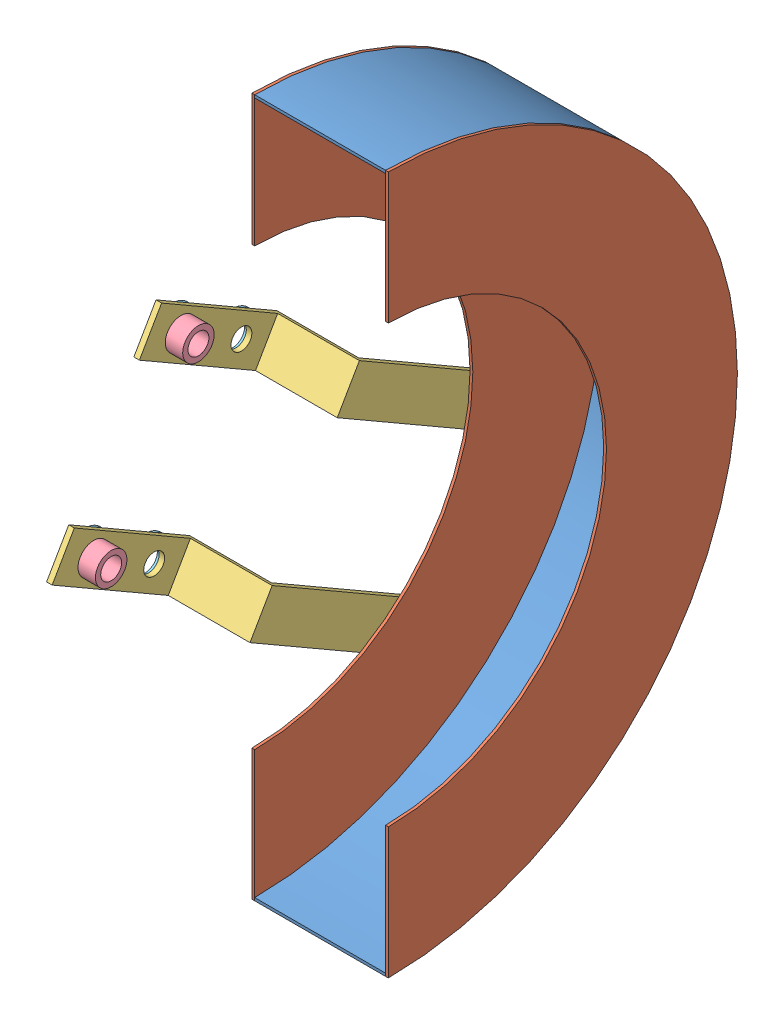
SolidWorks assembly 53model, configuration Default. Lengths in mm.
Overall size (130.17 400 267.8).
12 component instances, 5 part files, 17 mates.
Components (placement in the parent):
- 52model-1: 52model [Default] at (-9.646 -13.9168 14.5449) size (78.17 400 200)
  - GuardFlat-1: GuardFlat [Default] at (-13.9553 22.8327 72.0636) size (75 400 200)
  - GuardSide-1: GuardSide [Default] at (-15.5428 22.8327 72.0636) size (1.59 400 200)
  - GuardSide-2: GuardSide [Default] at (61.0447 22.8327 72.0636) size (1.59 400 200)
- GuardSupport-1: GuardSupport [Default] at (-75.1888 61.8019 104.2453) x (1 0 0) z (0 0.5 0.866025) size (50 25.4 236.83)
- GuardSupport-2: GuardSupport [Default] at (-75.1888 -24.8007 154.2453) x (1 0 0) z (0 0.5 0.866025) size (50 25.4 236.83)
- MediumNut-3: MediumNut [Default] at (-62.0138 -23.5423 130.4248) x (0 1 0) z (0 0 1) size (18 10 18)
- MediumNut-4: MediumNut [Default] at (-62.0138 63.0602 80.4248) x (0 1 0) z (0 0 1) size (18 10 18)
- 87model-1: 87model [Default] at (-77.1888 43.0602 45.7838) x (0 -1 0) z (0 0 1) size (25 2 25)
- 87model-2: 87model [Default] at (-77.1888 -23.5423 130.4248) x (0 -1 0) z (0 0 1) size (25 2 25)
- 87model-3: 87model [Default] at (-77.1888 63.0602 80.4248) x (0 -1 0) z (0 0 1) size (25 2 25)
- 87model-4: 87model [Default] at (-77.1888 -43.5423 95.7838) x (0 -1 0) z (0 0 1) size (25 2 25)
Mates (geometry in assembly coordinates):
- Coincident1: coincident anti-aligned: plane of 52model-1/GuardSide-1 through (-25.1888 8.9159 -353.5329) normal (-1 0 0); plane of GuardSupport-2 through (-25.1888 -121.2161 -63.5512) normal (1 0 0)
- Coincident2: coincident aligned: circle of 52model-1/GuardSide-1; plane of GuardSupport-1 through (-25.1888 -34.6136 -113.5512) normal (1 0 0)
- Distance1: distance = 100 mm aligned: plane of GuardSupport-1 through (-75.1888 61.8019 104.2453) normal (0 -0.866025 0.5); plane of GuardSupport-2 through (-75.1888 -24.8007 154.2453) normal (0 -0.866025 0.5)
- Coincident4: coincident: plane of GuardSupport-1 through (-72.0138 83.7989 91.5453) normal (0 0.5 0.866025); line of GuardSupport-2 through (-72.0138 -2.8036 141.5453) axis (0 -0.866025 0.5)
- Angle1: planar angle = 2.094395 rad aligned: plane of GuardSupport-1 through (-75.1888 83.7989 91.5453) normal (0 0.866025 -0.5); plane of 52model-1/GuardSide-1 through (-23.6013 8.9159 86.6085) normal (0 0 1)
- Concentric2: concentric anti-aligned: circle of GuardSupport-2; cylinder of MediumNut-3 through (-62.0138 -23.5423 130.4248) axis (-1 0 0) radius 6
- Concentric3: concentric anti-aligned: cylinder of GuardSupport-1 through (-97.4138 63.0602 80.4248) axis (1 0 0) radius 6; cylinder of MediumNut-4 through (-62.0138 63.0602 80.4248) axis (-1 0 0) radius 6
- Coincident7: coincident anti-aligned: plane of GuardSupport-2 through (-72.0138 -41.2161 75.0129) normal (1 0 0); plane of MediumNut-3 through (-72.0138 -23.5423 130.4248) normal (-1 0 0)
- Coincident8: coincident anti-aligned: plane of GuardSupport-1 through (-72.0138 45.3864 25.0129) normal (1 0 0); plane of MediumNut-4 through (-72.0138 63.0602 80.4248) normal (-1 0 0)
- Coincident9: coincident: plane of GuardSupport-1 through (-75.1888 83.7989 91.5453) normal (-1 0 0); plane of 87model-1 through (-75.1888 43.0602 45.7838) normal (1 0 0)
- Coincident10: coincident: plane of GuardSupport-1 through (-75.1888 83.7989 91.5453) normal (-1 0 0); plane of 87model-3 through (-75.1888 63.0602 80.4248) normal (1 0 0)
- Coincident11: coincident anti-aligned: plane of GuardSupport-1 through (-75.1888 83.7989 91.5453) normal (-1 0 0); plane of 87model-4 through (-75.1888 -43.5423 95.7838) normal (1 0 0)
- Coincident12: coincident anti-aligned: plane of GuardSupport-1 through (-75.1888 83.7989 91.5453) normal (-1 0 0); plane of 87model-2 through (-75.1888 -89.9515 46.8604) normal (1 0 0)
- Concentric4: concentric aligned: circle of GuardSupport-1; circle of 87model-1
- Concentric5: concentric aligned: circle of GuardSupport-1; circle of 87model-3
- Concentric6: concentric aligned: circle of GuardSupport-2; circle of 87model-4
- Concentric7: concentric aligned: circle of GuardSupport-2; circle of 87model-2
